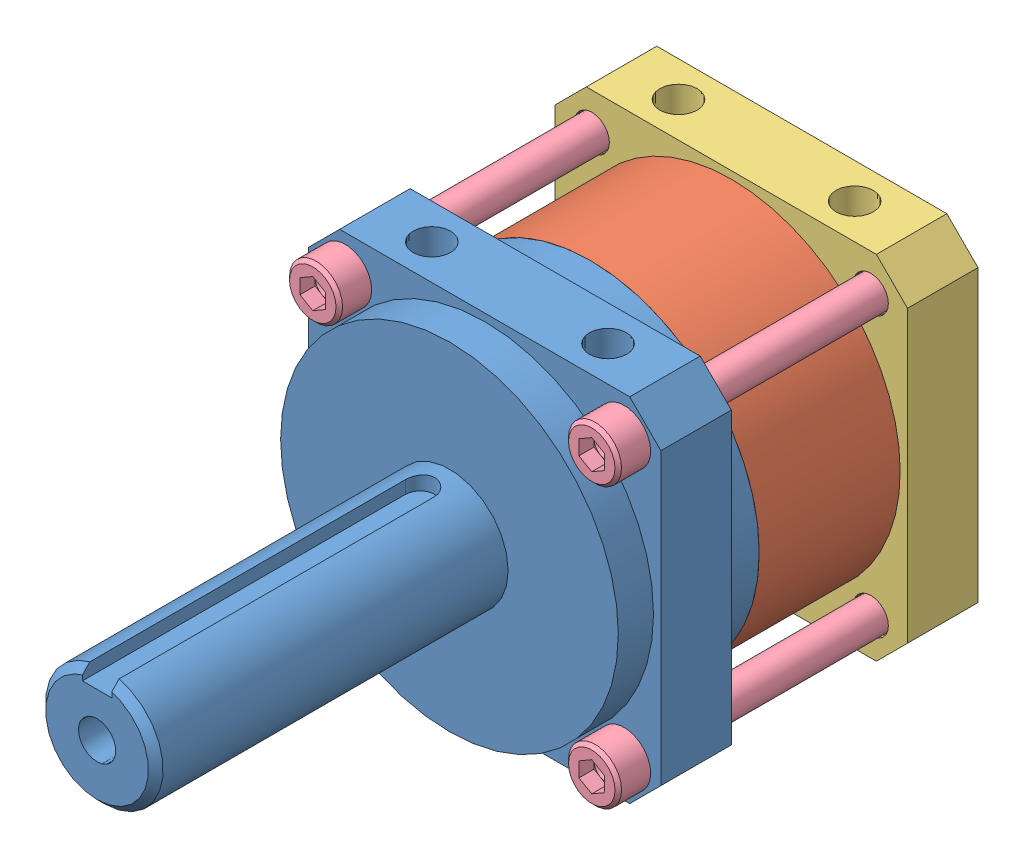
SolidWorks assembly am-2875+Banebots+P60+4-1, configuration Default. Lengths in mm.
Overall size (38.1 38.1 76.2).
7 component instances, 4 part files, 0 mates.
Components (placement in the parent):
- P60 shaft plate and shaft-1: P60 shaft plate and shaft [Default] at (1.6922 24.6308 41.3039) size (38.1 38.1 53.34)
- P60 1-stage ring gear-1: P60 1-stage ring gear [Default] at (1.6922 24.6308 26.0639) size (36.51 36.51 15.24)
- P60 motor plate-1: P60 motor plate [Default] at (1.6922 24.6308 10.8239) size (38.1 38.1 7.62)
- socket head cap screw_ai_HX-SHCS 0.138-32x1.25x0.75-N-1: socket head cap screw_ai_HX-SHCS 0.138-32x1.25x0.75-N [Default] at (-13.389 39.712 40.9991) x (0 0 -1) z (1 0 0) size (35.26 5.74 5.74)
- socket head cap screw_ai_HX-SHCS 0.138-32x1.25x0.75-N-2: socket head cap screw_ai_HX-SHCS 0.138-32x1.25x0.75-N [Default] at (16.7735 39.712 40.9991) x (0 0 -1) z (1 0 0) size (35.26 5.74 5.74)
- socket head cap screw_ai_HX-SHCS 0.138-32x1.25x0.75-N-3: socket head cap screw_ai_HX-SHCS 0.138-32x1.25x0.75-N [Default] at (-13.389 9.5495 40.9991) x (0 0 -1) z (1 0 0) size (35.26 5.74 5.74)
- socket head cap screw_ai_HX-SHCS 0.138-32x1.25x0.75-N-4: socket head cap screw_ai_HX-SHCS 0.138-32x1.25x0.75-N [Default] at (16.7735 9.5495 40.9991) x (0 0 -1) z (1 0 0) size (35.26 5.74 5.74)
